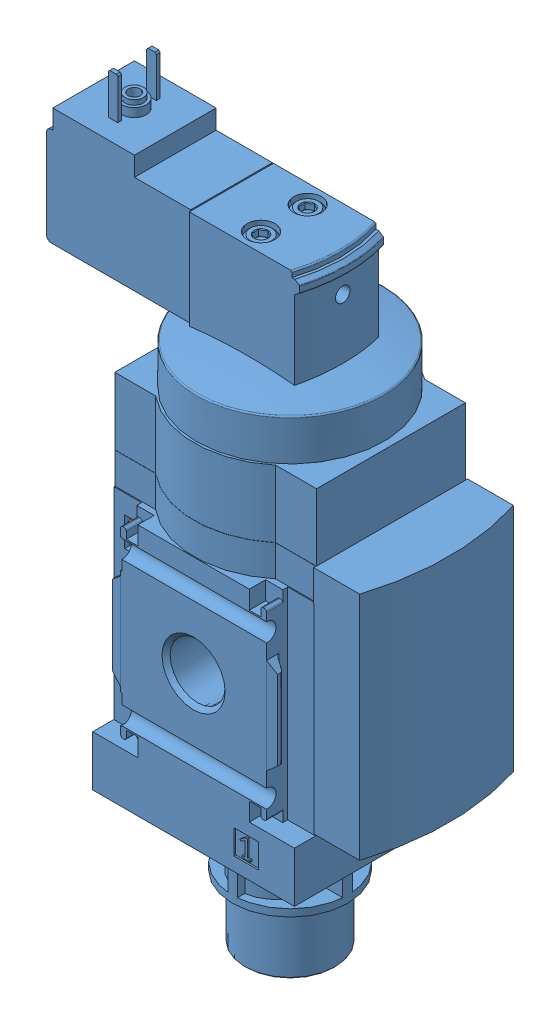
SolidWorks assembly 527709 MS4-EE-1_4-V24, configuration Default. Lengths in mm.
Overall size (75.2 142.8 40.2).
2 component instances, 2 part files, 0 mates.
Components (placement in the parent):
- 527709 MS4-EE-1_4-V24-0D-1: 527709 MS4-EE-1_4-V24-0D [Default] at origin size (75.2 142.8 40.2)
- 645204 MS4-1: 645204 MS4 [Default] at (-19 0 0) x (0 0 -1) z (-1 0 0) size (30.7 37.5 5.5)
